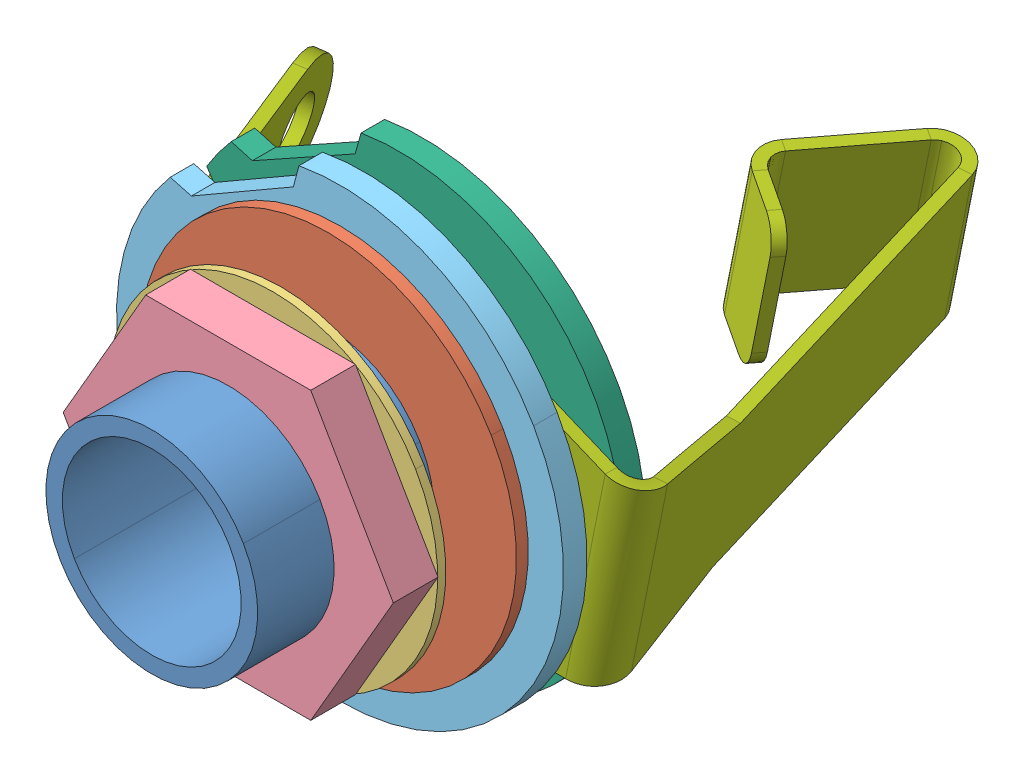
SolidWorks assembly Jack6_3, configuration Standard. Lengths in mm.
Overall size (31.79 26.22 30.76).
8 component instances, 8 part files, 17 mates.
Components (placement in the parent):
- Jack-6,35-Body-1: Jack-6,35-Body [Standard] at (7.0148 -6.075 0) x (0.866025 0.5 0) z (0 0 1) size (9 9 13.6)
- Jack-6,35-Washer-1: Jack-6,35-Washer [Standard] at (7.0148 -6.075 -8) x (0.866025 0.5 0) z (0 0 1) size (16 16 0.5)
- Jack-6,35-Washer-Outer-3: Jack-6,35-Washer-Outer [Standard] at (7.0148 -6.075 -5.5) x (0.866025 0.5 0) z (0 0 1) size (14 14 0.35)
- Jack-6,35-Nut-1: Jack-6,35-Nut [Standard] at (7.0148 -6.075 -5.15) x (0.866025 0.5 0) z (0 0 1) size (12.15 14.03 1.9)
- Jack-6,35-Housing-Outer-2: Jack-6,35-Housing-Outer [Standard] at (7.0148 -6.075 -9) x (0.866025 0.5 0) z (0 0 1) size (19 18.46 2)
- Jack-6,35-Washer-Inner-1: Jack-6,35-Washer-Inner [Standard] at (7.0148 -6.075 -11.5) x (-0.61771 0.786406 0) z (0 0 1) size (18.84 18.46 1)
- Jack-6,35-Connector-Tip-1: Jack-6,35-Connector-Tip [Standard] at (43.5437 -13.4084 -14.3779) x (-0.196829 -0.980438 0) z (-0.803128 0.161233 0.573576) size (14 19.8 22.29)
- Jack-6,35-Connector-Ground-1: Jack-6,35-Connector-Ground [Standard] at (7.0148 -6.075 -11.8) x (0.664833 -0.746992 0) z (0 0 -1) size (12 16.84 10.14)
Mates (geometry in assembly coordinates):
- Konzentrisch1: concentric anti-aligned: cylinder of Jack-6,35-Body-1 through (7.0148 -6.075 -7.5) axis (0 0 1) radius 4.5; cylinder of Jack-6,35-Nut-1 through (7.0148 -6.075 -0.25) axis (0 0 -1) radius 4.3
- Konzentrisch2: concentric anti-aligned: cylinder of Jack-6,35-Body-1 through (7.0148 -6.075 -7.5) axis (0 0 1) radius 4.5; cylinder of Jack-6,35-Washer-Outer-3 through (7.0148 -6.075 -2.15) axis (0 0 -1) radius 4.75
- Konzentrisch3: concentric anti-aligned: cylinder of Jack-6,35-Body-1 through (7.0148 -6.075 -7.5) axis (0 0 1) radius 4.5; cylinder of Jack-6,35-Washer-1 through (7.0148 -6.075 -7.5) axis (0 0 -1) radius 4
- Konzentrisch4: concentric anti-aligned: cylinder of Jack-6,35-Body-1 through (7.0148 -6.075 -10.6) axis (0 0 1) radius 4; cylinder of Jack-6,35-Housing-Outer-2 through (7.0148 -6.075 -8) axis (0 0 -1) radius 4
- Konzentrisch5: concentric anti-aligned: cylinder of Jack-6,35-Housing-Outer-2 through (7.0148 -6.075 -10) axis (0 0 1) radius 4.5; cylinder of Jack-6,35-Connector-Tip-1 through (7.0148 -6.075 -10) axis (0 0 -1) radius 4
- Konzentrisch6: concentric anti-aligned: cylinder of Jack-6,35-Body-1 through (7.0148 -6.075 -10.6) axis (0 0 1) radius 4; cylinder of Jack-6,35-Washer-Inner-1 through (7.0148 -6.075 -10.5) axis (0 0 -1) radius 4
- Konzentrisch7: concentric anti-aligned: cylinder of Jack-6,35-Body-1 through (7.0148 -6.075 -10.6) axis (0 0 1) radius 4; cylinder of Jack-6,35-Connector-Ground-1 through (7.0148 -6.075 -11.5) axis (0 0 -1) radius 4
- Deckungsgleich2: coincident anti-aligned: plane of Jack-6,35-Washer-Inner-1 through (7.0148 -6.075 -11.5) normal (0 0 -1); plane of Jack-6,35-Connector-Ground-1 through (-4.1901 -16.0475 -11.5) normal (0 0 1)
- Deckungsgleich3: coincident anti-aligned: plane of Jack-6,35-Washer-Inner-1 through (7.0148 -6.075 -10.5) normal (0 0 1); plane of Jack-6,35-Connector-Tip-1 through (-7.6918 -3.1226 -10.5) normal (0 0 -1)
- Deckungsgleich4: coincident anti-aligned: plane of Jack-6,35-Housing-Outer-2 through (7.0148 -6.075 -10) normal (0 0 -1); plane of Jack-6,35-Connector-Tip-1 through (-7.6918 -3.1226 -10) normal (0 0 1)
- Deckungsgleich5: coincident anti-aligned: plane of Jack-6,35-Washer-1 through (7.0148 -6.075 -8) normal (0 0 -1); plane of Jack-6,35-Housing-Outer-2 through (7.0148 -6.075 -8) normal (0 0 1)
- Deckungsgleich8: coincident anti-aligned: plane of Jack-6,35-Body-1 through (7.0148 -6.075 -7.5) normal (0 0 -1); plane of Jack-6,35-Washer-1 through (7.0148 -6.075 -7.5) normal (0 0 1)
- Deckungsgleich9: coincident anti-aligned: plane of Jack-6,35-Washer-Outer-3 through (7.0148 -6.075 -2.15) normal (0 0 1); plane of Jack-6,35-Nut-1 through (7.0148 -6.075 -2.15) normal (0 0 -1)
- Deckungsgleich10: coincident aligned: plane of Jack-6,35-Body-1 through (7.0148 -6.075 0) normal (0 0 1); plane of assembly through (0 0 0) normal (0 0 1)
- Deckungsgleich11: coincident aligned: plane of Jack-6,35-Nut-1 through (10.5222 0 -0.25) normal (0 1 0); plane of assembly through (0 0 0) normal (0 1 0)
- Deckungsgleich12: coincident: line of ? through (0 -6.075 -2.15) axis (0 0 1)
- LimitAbstand1: limit distance = 2 mm anti-aligned: plane of Jack-6,35-Washer-1 through (7.0148 -6.075 -7.5) normal (0 0 1); plane of Jack-6,35-Washer-Outer-3 through (7.0148 -6.075 -5.5) normal (0 0 -1)
